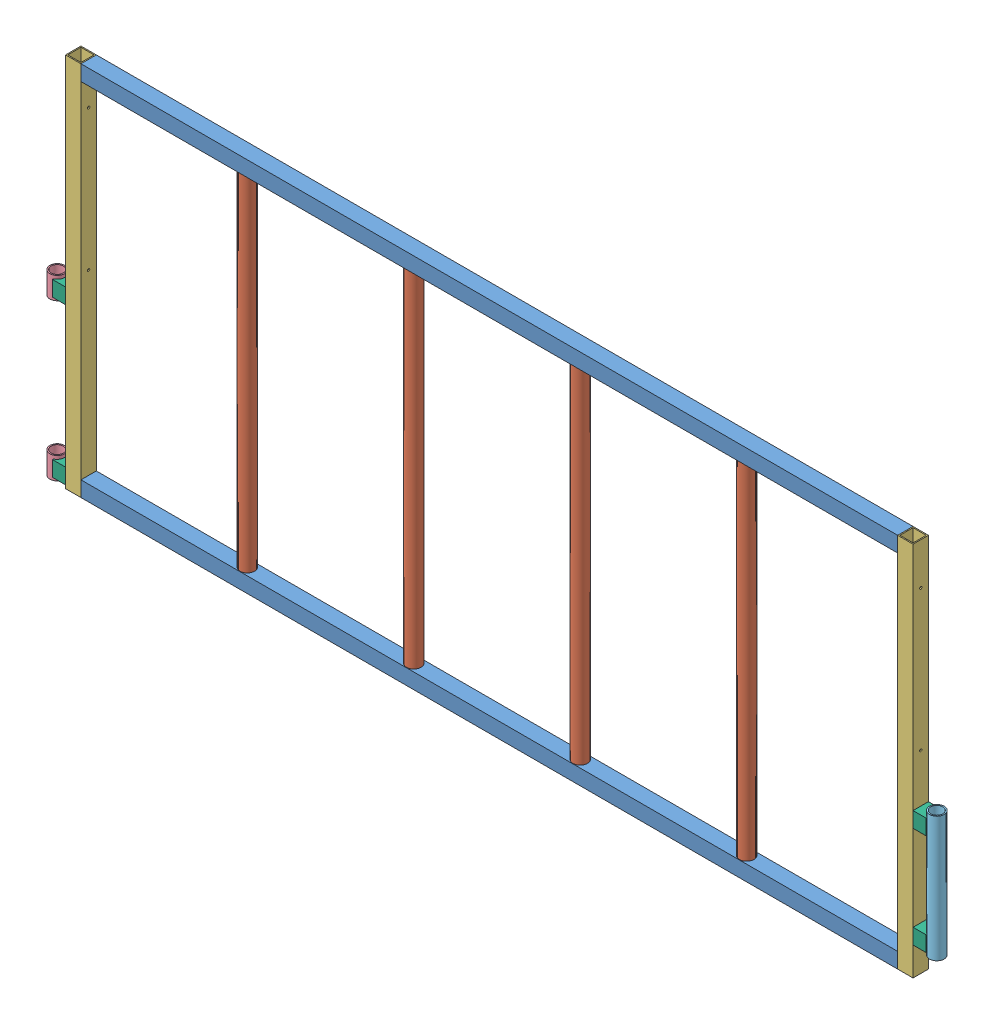
SolidWorks assembly GE-22002, configuration Default. Lengths in mm.
Overall size (2590.93 1085.85 55.12).
15 component instances, 6 part files, 30 mates.
Components (placement in the parent):
- GE-22002-01-1: GE-22002-01 [Default] at (-34.2836 1783.695 2324.307) size (2360.42 44.45 44.45)
- GE-22002-01-2: GE-22002-01 [Default] at (-34.2836 742.295 2324.307) size (2360.42 44.45 44.45)
- GE-22002-02-1: GE-22002-02 [Default] at (424.4404 786.745 2346.532) size (42.16 996.95 42.16)
- GE-22002-02-2: GE-22002-02 [Default] at (905.4529 786.745 2346.532) size (42.16 996.95 42.16)
- GE-22002-02-3: GE-22002-02 [Default] at (1386.4654 786.745 2346.532) size (42.16 996.95 42.16)
- GE-22002-02-4: GE-22002-02 [Default] at (1867.4779 786.745 2346.532) size (42.16 996.95 42.16)
- GE-22002-03-1: GE-22002-03 [Default] at (-34.2836 742.295 2324.307) x (0 1 0) z (0 0 1) size (1085.85 44.45 44.45)
- GE-22002-03-2: GE-22002-03 [Default] at (2370.5884 742.295 2324.307) x (0 1 0) z (0 0 1) size (1085.85 44.45 44.45)
- GE-22002-04-1: GE-22002-04 [Default] at (-125.2156 742.295 2346.532) size (42.16 63.5 42.16)
- GE-22002-04-2: GE-22002-04 [Default] at (-125.2156 1193.145 2346.532) x (0.923425 0 -0.383778) z (0.383778 0 0.923425) size (42.16 63.5 42.16)
- GE-22002-05-1: GE-22002-05 [Default] at (2417.0704 812.145 2346.532) size (42.16 361.95 42.16)
- GE-22002-06-1: GE-22002-06 [Default] at (2370.5884 1116.945 2346.532) size (38.1 44.45 44.45)
- GE-22002-06-2: GE-22002-06 [Default] at (2370.5884 824.845 2346.532) size (38.1 44.45 44.45)
- GE-22002-06-3: GE-22002-06 [Default] at (-78.7336 1202.67 2346.532) x (-1 0 0) z (0 0 -1) size (38.1 44.45 44.45)
- GE-22002-06-4: GE-22002-06 [Default] at (-78.7336 751.82 2346.532) x (-1 0 0) z (0 0 -1) size (38.1 44.45 44.45)
Mates (geometry in assembly coordinates):
- Coincident1: coincident anti-aligned: plane of Grille-01-2 through (-34.2836 786.745 2368.757) normal (0 1 0); plane of GE-22002-02-1 through (424.4404 786.745 2346.532) normal (0 -1 0)
- Distance1: distance = 22.225 mm aligned: plane of Grille-02-1 through (424.4404 786.745 2346.532) normal (0 0 1); plane of Grille-01-2 through (-34.2836 742.295 2368.757) normal (0 0 1)
- Distance2: distance = 458.724 mm anti-aligned: plane of Grille-02-1 through (424.4404 786.745 2346.532) normal (1 0 0); plane of Grille-01-2 through (-34.2836 742.295 2368.757) normal (-1 0 0)
- Coincident4: coincident anti-aligned: plane of Grille-01-1 through (-34.2836 1783.695 2368.757) normal (0 -1 0); plane of GE-22002-02-1 through (424.4404 1783.695 2346.532) normal (0 1 0)
- Coincident5: coincident aligned: plane of Grille-01-1 through (-34.2836 1783.695 2368.757) normal (0 0 1); plane of Grille-01-2 through (-34.2836 742.295 2368.757) normal (0 0 1)
- Coincident6: coincident aligned: plane of Grille-01-1 through (-34.2836 1783.695 2368.757) normal (-1 0 0); plane of Grille-01-2 through (-34.2836 742.295 2368.757) normal (-1 0 0)
- Coincident7: coincident anti-aligned: plane of Grille-01-2 through (-34.2836 742.295 2368.757) normal (-1 0 0); plane of GE-22002-03-1 through (-34.2836 742.295 2368.757) normal (1 0 0)
- Coincident8: coincident aligned: plane of Grille-01-2 through (-34.2836 742.295 2368.757) normal (0 0 1); plane of GE-22002-03-1 through (-34.2836 742.295 2368.757) normal (0 0 1)
- Coincident9: coincident aligned: plane of Grille-01-2 through (-34.2836 742.295 2368.757) normal (0 -1 0); plane of GE-22002-03-1 through (-34.2836 742.295 2368.757) normal (0 -1 0)
- Coincident11: coincident anti-aligned: plane of Grille-01-2 through (2326.1384 742.295 2368.757) normal (1 0 0); plane of GE-22002-03-2 through (2326.1384 742.295 2368.757) normal (-1 0 0)
- Coincident12: coincident aligned: plane of Grille-01-2 through (-34.2836 742.295 2368.757) normal (0 0 1); plane of GE-22002-03-2 through (2370.5884 742.295 2368.757) normal (0 0 1)
- Coincident13: coincident aligned: plane of Grille-01-2 through (-34.2836 742.295 2368.757) normal (0 -1 0); plane of GE-22002-03-2 through (2370.5884 742.295 2368.757) normal (0 -1 0)
- Distance4: distance = 69.85 mm aligned: plane of GE-22002-03-1 through (-34.2836 742.295 2368.757) normal (0 -1 0); plane of Grille-05-1 through (2417.0704 812.145 2346.532) normal (0 -1 0)
- Coincident17: coincident aligned: plane of GE-22002-03-2 through (2370.5884 742.295 2368.757) normal (0 -1 0); plane of Grille-04-1 through (-125.2156 742.295 2346.532) normal (0 -1 0)
- Distance6: distance = 450.85 mm aligned: plane of Grille-04-2 through (-125.2156 1193.145 2346.532) normal (0 -1 0); plane of GE-22002-03-2 through (2370.5884 742.295 2368.757) normal (0 -1 0)
- Coincident18: coincident anti-aligned: plane of GE-22002-03-2 through (2370.5884 742.295 2368.757) normal (1 0 0); plane of GE-22002-06-2 through (2370.5884 869.295 2346.532) normal (-1 0 0)
- Coincident19: coincident aligned: plane of GE-22002-03-2 through (2370.5884 742.295 2368.757) normal (0 0 1); plane of GE-22002-06-2 through (2370.5884 869.295 2368.757) normal (0 0 1)
- Coincident20: coincident aligned: plane of GE-22002-03-2 through (2370.5884 742.295 2368.757) normal (0 0 1); plane of GE-22002-06-1 through (2370.5884 1161.395 2368.757) normal (0 0 1)
- Coincident21: coincident anti-aligned: plane of GE-22002-03-2 through (2370.5884 742.295 2368.757) normal (1 0 0); plane of GE-22002-06-1 through (2370.5884 1161.395 2346.532) normal (-1 0 0)
- Distance7: distance = 12.7 mm aligned: plane of GE-22002-06-2 through (2370.5884 824.845 2346.532) normal (0 -1 0); plane of Grille-05-1 through (2417.0704 812.145 2346.532) normal (0 -1 0)
- Distance8: distance = 12.7 mm aligned: plane of GE-22002-06-1 through (2370.5884 1161.395 2346.532) normal (0 1 0); plane of Grille-05-1 through (2417.0704 1174.095 2346.532) normal (0 1 0)
- Concentric2: concentric aligned: cylinder of Grille-05-1 through (2417.0704 1174.095 2346.532) axis (0 -1 0) radius 21.082; cylinder of GE-22002-06-1 through (2417.0704 1161.395 2346.532) axis (0 -1 0) radius 21.082
- Coincident24: coincident anti-aligned: plane of GE-22002-03-1 through (-78.7336 742.295 2368.757) normal (-1 0 0); plane of GE-22002-06-4 through (-78.7336 796.27 2346.532) normal (1 0 0)
- Coincident25: coincident aligned: plane of GE-22002-03-1 through (-34.2836 742.295 2368.757) normal (0 0 1); plane of GE-22002-06-4 through (-78.7336 796.27 2368.757) normal (0 0 1)
- Distance9: distance = 9.525 mm aligned: plane of GE-22002-06-4 through (-78.7336 796.27 2346.532) normal (0 1 0); plane of Grille-04-1 through (-125.2156 805.795 2346.532) normal (0 1 0)
- Concentric4: concentric aligned: cylinder of Grille-04-1 through (-125.2156 805.795 2346.532) axis (0 -1 0) radius 21.082; cylinder of GE-22002-06-4 through (-125.2156 796.27 2346.532) axis (0 -1 0) radius 21.082
- Coincident27: coincident anti-aligned: plane of GE-22002-03-1 through (-78.7336 742.295 2368.757) normal (-1 0 0); plane of GE-22002-06-3 through (-78.7336 1247.12 2346.532) normal (1 0 0)
- Coincident28: coincident aligned: plane of GE-22002-03-1 through (-34.2836 742.295 2368.757) normal (0 0 1); plane of GE-22002-06-3 through (-78.7336 1247.12 2368.757) normal (0 0 1)
- Distance10: distance = 9.525 mm aligned: plane of GE-22002-06-3 through (-78.7336 1247.12 2346.532) normal (0 1 0); plane of Grille-04-2 through (-125.2156 1256.645 2346.532) normal (0 1 0)
- Concentric5: concentric aligned: cylinder of GE-22002-04-2 through (-125.2156 1256.645 2346.532) axis (0 -1 0) radius 21.082; cylinder of GE-22002-06-3 through (-125.2156 1247.12 2346.532) axis (0 -1 0) radius 21.082
